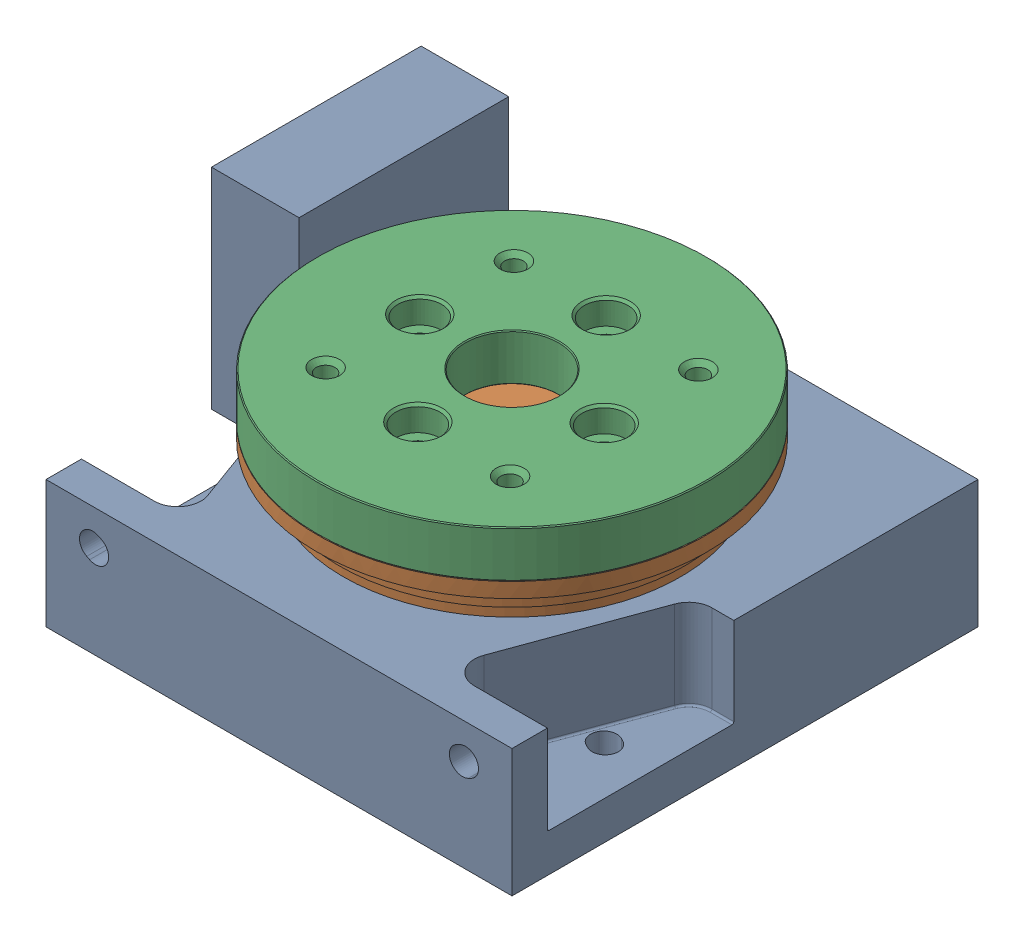
SolidWorks assembly 4in_stage, configuration ART310-U. Lengths in mm.
Overall size (165.49 60.96 150.14).
3 component instances, 3 part files, 5 mates.
Components (placement in the parent):
- 4in_stage_base-1: 4in_stage_base [NO APERTURE] x (0 0 1) z (0 1 0) size (129.16 153.92 59.06)
- 4in_stage_plate1-1: 4in_stage_plate1 [ART310-U] x (0.010381 0 -0.999946) z (0 1 0) size (106.17 106.17 13.46)
- 4in_stage_plate2-1: 4in_stage_plate2 [Default] at (0 60.96 0) x (0.699728 0 0.714409) z (-0.714409 0 0.699728) size (106.17 12.7 106.17)
Mates (geometry in assembly coordinates):
- Coincident4: coincident anti-aligned: plane of base-1 through (0 34.802 0) normal (0 1 0); plane of stage-1 through (-62.8374 34.802 -64.1558) normal (0 -1 0)
- Concentric1: concentric aligned: line of base-1 through (64.9605 0 -2.9527) axis (0 0 1); cylinder of stage-1 through (0 48.26 0) axis (0 1 0) radius 3.175
- Concentric2: concentric aligned: cylinder of stage-1 through (-25.3986 48.26 -0.2637) axis (0 1 0) radius 3.175; cylinder of stage2-1 through (-25.3986 60.96 -0.2637) axis (0 1 0) radius 3.2639
- Concentric3: concentric aligned: cylinder of stage-1 through (0 48.26 0) axis (0 1 0) radius 3.175; cylinder of stage2-1 through (0 48.26 0) axis (0 1 0) radius 12.7
- Coincident5: coincident anti-aligned: plane of stage-1 through (0 48.26 0) normal (0 1 0); plane of stage2-1 through (0 48.26 0) normal (0 -1 0)
